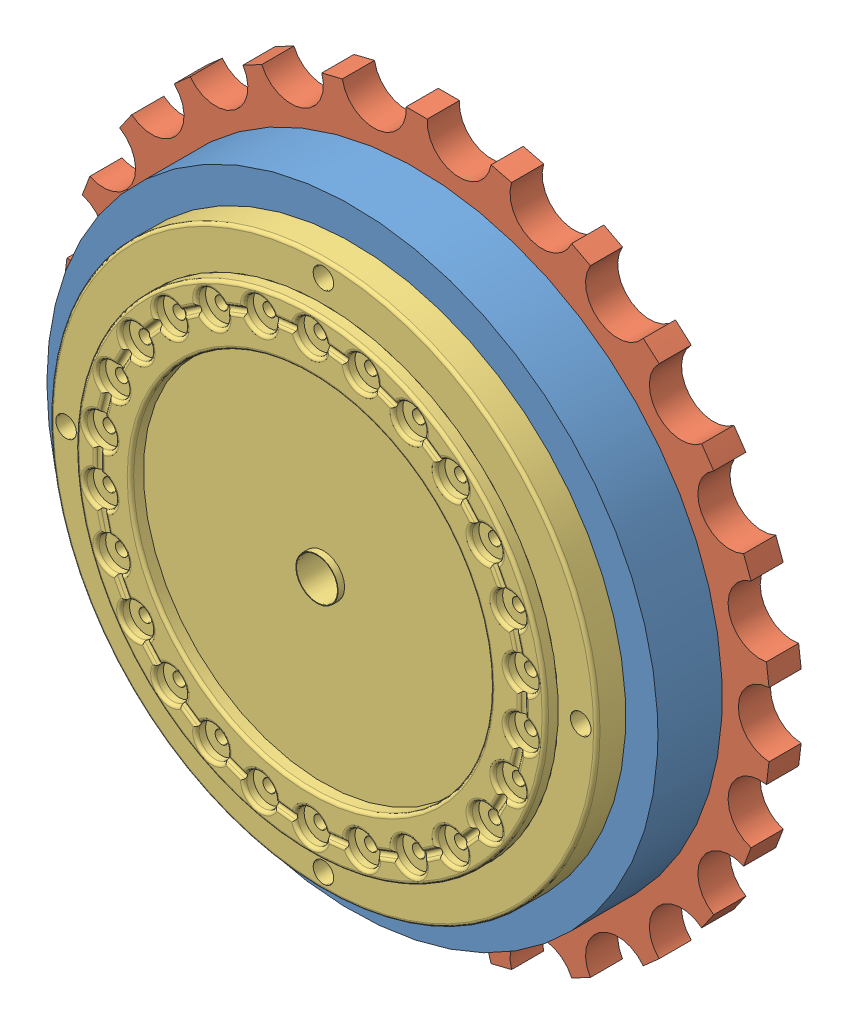
SolidWorks assembly Assemblage2, configuration Défaut. Lengths in mm.
Overall size (10.95 11 2.81).
4 component instances, 3 part files, 8 mates.
Components (placement in the parent):
- le vrai du v P2-1: le vrai du v P2 [Défaut] at (-0.3825 1.4025 9.5) size (9.5 9.5 1)
- le vrai du v P3-1: le vrai du v P3 [Défaut] at (-0.3825 1.4025 9.5) x (0 1 0) z (-1 0 0) size (11 0.5 10.95)
- le vrai du v-1: le vrai du v [Défaut] at (-0.3825 1.4025 10.5) size (8.5 8.5 0.65)
- le vrai du v-2: le vrai du v [Défaut] at (-0.3825 1.4025 9) x (0 -1 0) z (0 0 -1) size (8.5 8.5 0.65)
Mates (geometry in assembly coordinates):
- Coïncidente2: coincident: plane of le vrai du v P2-1 through (-0.3825 1.4025 10.5) normal (0 0 1); plane of le vrai du v-1 through (-0.3825 1.4025 10.5) normal (0 0 -1)
- Coïncidente3: coincident: circle of le vrai du v P2-1; circle of le vrai du v-1
- Coïncidente4: coincident aligned: circle of le vrai du v P2-1; circle of le vrai du v-1
- Coïncidente6: coincident: plane of le vrai du v P2-1 through (-0.3825 1.4025 9.5) normal (0 0 -1); plane of le vrai du v P3-1 through (-0.3825 1.4025 9.5) normal (0 0 1)
- Coïncidente7: coincident: circle of le vrai du v P2-1; circle of le vrai du v P3-1
- Coïncidente8: coincident anti-aligned: circle of le vrai du v P2-1; circle of le vrai du v P3-1
- Coïncidente9: coincident: circle of le vrai du v P3-1; circle of le vrai du v-2
- Coïncidente10: coincident aligned: circle of le vrai du v P3-1; circle of le vrai du v-2
